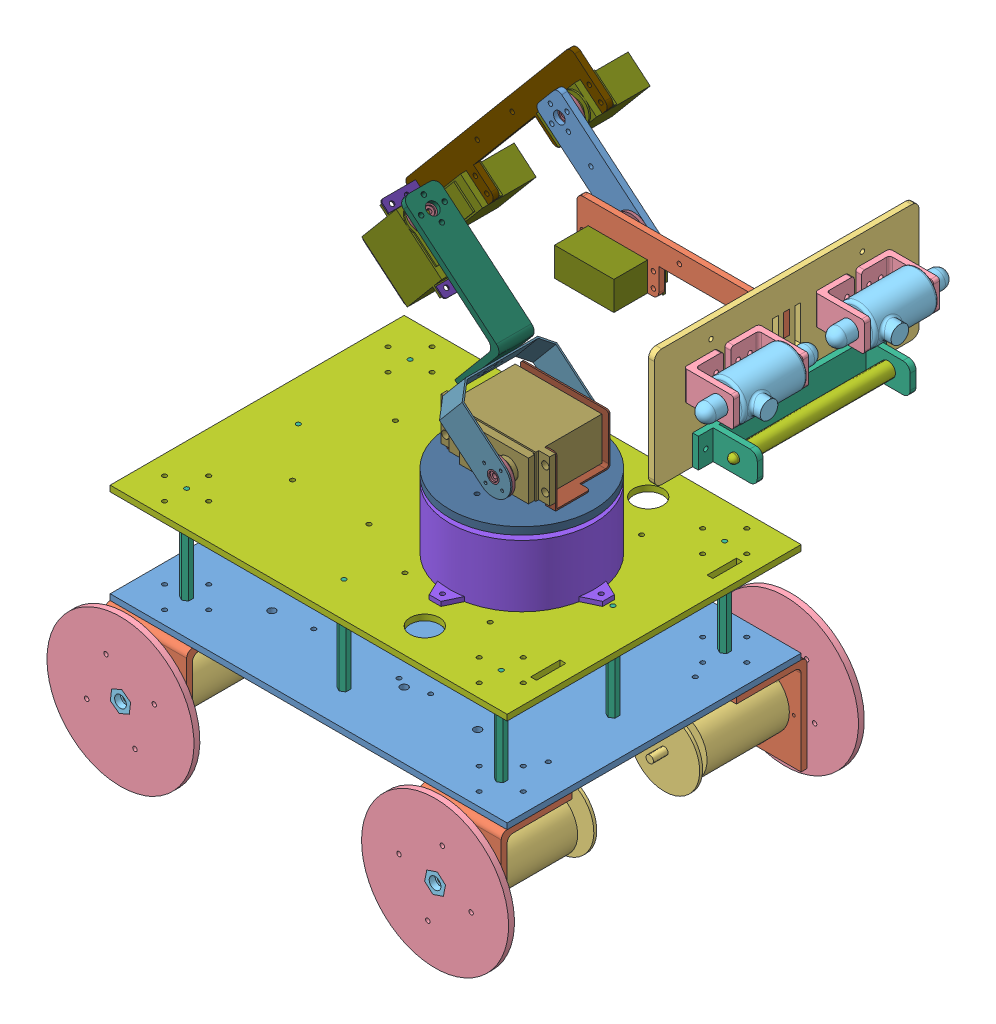
SolidWorks assembly robot_config5, configuration Default. Lengths in mm.
Overall size (452.85 463.23 242).
55 component instances, 25 part files, 137 mates.
Components (placement in the parent):
- base_odroid_down_fix-1: base_odroid_down_fix [Default] at (39.4639 122.941 229.7749) x (1 0 0) z (0 -1 0) size (270 200 4)
- link_motor_1_port-1: link_motor_1_port [Default] at (221.3654 112.3394 287.3354) x (0 0 -1) z (1 0 0) size (48 66 56)
- motor_dc_NISCA-1: motor_dc_NISCA [Default] at (244.2642 39.7289 313.6416) x (0 -1 0) z (0 0 -1) size (54 48 92)
- roda_shaft-1: roda_shaft [Default] at (185.8398 121.6563 330.6416) x (-0.980223 0.197896 0) z (0 0 1) size (100 100 4)
- shaft_adapter_5mm-1: shaft_adapter_5mm [Default] at (248.7954 72.9583 317.6416) x (0.980223 -0.197896 0) z (0 0 1) size (13 15.01 17)
- link_motor_1_port-2: link_motor_1_port [Default] at (221.3654 112.3394 139.9479) x (0 0 1) z (-1 0 0) size (48 66 56)
- motor_dc_NISCA-2: motor_dc_NISCA [Default] at (198.4666 39.7289 113.6416) x (0 -1 0) z (0 0 1) size (54 48 92)
- shaft_adapter_5mm-3: shaft_adapter_5mm [Default] at (238.0112 59.5291 109.6416) x (0.404857 -0.91438 0) z (0 0 -1) size (13 15.01 17)
- roda_shaft-2: roda_shaft [Default] at (222.1063 135.748 96.6416) x (0.589448 0.807807 0) z (0 0 -1) size (100 100 4)
- link_motor_1_port-5: link_motor_1_port [Default] at (7.3654 112.3394 287.3354) x (0 0 -1) z (1 0 0) size (48 66 56)
- motor_dc_NISCA-5: motor_dc_NISCA [Default] at (-15.5334 128.1531 313.6416) x (0 1 0) z (0 0 -1) size (54 48 92)
- roda_shaft-5: roda_shaft [Default] at (51.5287 56.8466 334.6416) x (0.393495 -0.919327 0) z (0 0 -1) size (100 100 4)
- shaft_adapter_5mm-6: shaft_adapter_5mm [Default] at (0.8367 112.7577 317.6416) x (-0.393495 0.919327 0) z (0 0 1) size (13 15.01 17)
- link_motor_1_port-6: link_motor_1_port [Default] at (7.3654 112.3394 139.9479) x (0 0 1) z (-1 0 0) size (48 66 56)
- motor_dc_NISCA-6: motor_dc_NISCA [Default] at (-15.5334 39.7289 113.6416) x (0 -1 0) z (0 0 1) size (54 48 92)
- roda_shaft-6: roda_shaft [Default] at (45.258 48.6046 96.6416) x (0.202799 -0.97922 0) z (0 0 -1) size (100 100 4)
- shaft_adapter_5mm-7: shaft_adapter_5mm [Default] at (36.6325 79.8838 109.6416) x (0.949429 -0.313981 0) z (0 0 -1) size (13 15.01 17)
- spacer_6cm-2: spacer_6cm [Default] at (221.7099 182.941 288.7798) x (0.5 0 -0.866025) z (0 -1 0) size (6 6.93 68)
- spacer_6cm-3: spacer_6cm [Default] at (114.7099 182.941 288.7798) x (0.5 0 -0.866025) z (0 -1 0) size (6 6.93 68)
- spacer_6cm-4: spacer_6cm [Default] at (7.7099 182.941 288.7798) x (0.5 0 -0.866025) z (0 -1 0) size (6 6.93 68)
- spacer_6cm-5: spacer_6cm [Default] at (221.7099 182.941 212.7798) x (0.5 0 -0.866025) z (0 -1 0) size (6 6.93 68)
- spacer_6cm-7: spacer_6cm [Default] at (7.7099 182.941 212.7798) x (0.5 0 -0.866025) z (0 -1 0) size (6 6.93 68)
- spacer_6cm-8: spacer_6cm [Default] at (221.7099 182.941 136.7798) x (0.5 0 -0.866025) z (0 -1 0) size (6 6.93 68)
- spacer_6cm-9: spacer_6cm [Default] at (114.7099 182.941 136.7798) x (0.5 0 -0.866025) z (0 -1 0) size (6 6.93 68)
- spacer_6cm-10: spacer_6cm [Default] at (7.7099 182.941 136.7798) x (0.5 0 -0.866025) z (0 -1 0) size (6 6.93 68)
- base_odroid_up_fix-1: base_odroid_up_fix [Default] at (186.1287 186.941 197.5083) x (-1 0 0) z (0 -1 0) size (270 200 4)
- base_arm-1: base_arm [Default] at (159.3654 194.0898 219.4289) x (0 0 1) z (-1 0 0) size (118.01 42 118.01)
- servo_hs422-1: servo_hs422 [Default] at (169.6524 210.6756 203.7356) x (0 0 1) z (-1 0 0) size (19.81 42.14 58.23)
- link1_arm-1: link1_arm [Default] at (132.7148 232.0663 213.6416) x (-1 0 0) z (0 1 0) size (98 98 12)
- bracket_servo_hs755-1: bracket_servo_hs755 [Default] at (196.3654 266.4802 252.854) x (0 0 1) z (-1 0 0) size (44 34 74)
- servo_hs755-1: servo_hs755 [Default] at (169.4663 211.9363 188.6416) x (0 -1 0) z (0 0 1) size (29 74 56.99)
- servo_horn_general-1: servo_horn_general [Default] at (212.6751 229.4848 247.6316) x (0.766044 -0.642788 0) z (0 0 -1) size (24 24 6)
- link2_ubracket-2: link2_ubracket [Default] at (137.2903 272.9307 202.3382) x (0 0 -1) z (0.642788 0.766044 0) size (66 59 24)
- link2_fix-2: link2_fix [Default] at (95.2497 313.4968 203.2174) x (-0.642788 -0.766044 0) z (0 0 1) size (45.14 89 24)
- servo_horn_general-2: servo_horn_general [Default] at (133.6428 328.2076 212.0424) x (0.766044 -0.642788 0) z (-0.642788 -0.766044 0) size (24 24 6)
- servo_hs645-2: servo_hs645 [Default] at (36.495 351.8235 228.4385) x (-0.766044 0.642788 0) z (0.642788 0.766044 0) size (53.34 19.56 42.35)
- bracket_servo_645-2: bracket_servo_645 [Default] at (85.4438 371.1492 209.3754) x (0.642788 0.766044 0) z (0.766044 -0.642788 0) size (34 24 57)
- servo_horn_general-3: servo_horn_general [Default] at (114.2751 302.95 201.2504) x (0.573576 -0.819152 0) z (0 0 -1) size (24 24 6)
- servo_hs645-3: servo_hs645 [Default] at (67.4404 298.0108 156.8959) x (-0.642788 -0.766044 0) z (0 0 1) size (53.34 19.56 42.35)
- link4_fix-1: link4_fix [Default] at (217.9489 486.4381 185.4709) x (0.642788 0.766044 0) z (0 0 1) size (176.25 35 4)
- servo_hs645-4: servo_hs645 [Default] at (193.9848 489.1669 156.8959) x (0.642788 0.766044 0) z (0 0 1) size (53.34 19.56 42.35)
- link5_fix-1: link5_fix [Default] at (223.23 467.7473 201.2504) x (0.642788 0.766044 0) z (0 0 1) size (24 90 4)
- servo_horn_general-4: servo_horn_general [Default] at (138.7232 475.3817 201.2504) x (-0.766044 0.642788 0) z (0 0 -1) size (24 24 6)
- servo_horn_general-5: servo_horn_general [Default] at (260.8198 372.9304 205.2504) x (0.766044 -0.642788 0) z (0 0 1) size (24 24 6)
- servo_hs645-5: servo_hs645 [Default] at (184.1852 418.5973 249.6049) x (-1 0 0) z (0 0 -1) size (53.34 19.56 42.35)
- link6_eff-1: link6_eff [Default] at (190.8717 398.4857 226.6809) x (-1 0 0) z (0 0 -1) size (140.63 35 4)
- base_link_effector_fix-2: base_link_effector_fix [Default] at (346.5728 431.9683 227.3815) x (0 0 -1) z (1 0 0) size (180 80 4)
- base_webcam_fix1-2: base_webcam_fix1 [Default] at (350.5728 432.3512 294.6809) x (0 0 -1) z (0 -1 0) size (23 34 20)
- base_webcam_fix1-3: base_webcam_fix1 [Default] at (350.5728 412.3512 243.6809) x (0 0 1) z (0 1 0) size (23 34 20)
- base_webcam_fix1-4: base_webcam_fix1 [Default] at (350.5728 432.3512 205.6809) x (0 0 -1) z (0 -1 0) size (23 34 20)
- base_webcam_fix1-5: base_webcam_fix1 [Default] at (350.5728 412.3512 154.6809) x (0 0 1) z (0 1 0) size (23 34 20)
- webcam_sturdy-3: webcam_sturdy [Default] at (374.5728 422.3512 243.37) x (0 0 -1) z (1 0 0) size (79 27 33.5)
- webcam_sturdy-4: webcam_sturdy [Default] at (374.5728 422.3512 154.37) x (0 0 -1) z (1 0 0) size (79 27 33.5)
- base_GM-1: base_GM [Default] at (358.8201 390.8512 184.9491) x (0 0 -1) z (0 -1 0) size (128 34 20)
- tabung_GM-1: tabung_GM [Default] at (418.1614 373.2473 174.6809) x (0.998525 0.054289 0) z (0 0 1) size (10 10 116)
Mates (geometry in assembly coordinates):
- Coincident1: coincident anti-aligned: plane of link_motor_1_port-1 through (193.3654 52.941 313.6416) normal (0 0 -1); plane of motor_dc_NISCA-1 through (221.3654 83.941 313.6416) normal (0 0 1)
- Concentric1: concentric aligned: cylinder of link_motor_1_port-1 through (221.3654 83.941 317.6416) axis (0 0 -1) radius 9.5; cylinder of motor_dc_NISCA-1 through (221.3654 83.941 317.6416) axis (0 0 -1) radius 9
- Concentric2: concentric anti-aligned: cylinder of link_motor_1_port-1 through (221.3654 106.941 317.6416) axis (0 0 -1) radius 1; cylinder of motor_dc_NISCA-1 through (221.3654 106.941 311.6416) axis (0 0 1) radius 1.5
- Coincident2: coincident anti-aligned: plane of motor_dc_NISCA-1 through (244.2642 39.7289 317.6416) normal (0 0 1); plane of shaft_adapter_5mm-1 through (221.3654 83.941 317.6416) normal (0 0 -1)
- Concentric4: concentric aligned: cylinder of motor_dc_NISCA-1 through (221.3654 83.941 330.6416) axis (0 0 -1) radius 2.5; cylinder of shaft_adapter_5mm-1 through (221.3654 83.941 330.6416) axis (0 0 -1) radius 2.5
- Coincident3: coincident anti-aligned: plane of roda_shaft-1 through (222.8507 91.2981 330.6416) normal (0.318728 -0.947846 0); plane of shaft_adapter_5mm-1 through (222.8507 91.2981 334.6416) normal (-0.318728 0.947846 0)
- Coincident4: coincident aligned: plane of roda_shaft-1 through (221.3654 83.941 334.6416) normal (0 0 1); plane of shaft_adapter_5mm-1 through (248.7954 72.9583 334.6416) normal (0 0 1)
- Coincident7: coincident anti-aligned: plane of roda_shaft-1 through (214.2513 81.5488 330.6416) normal (0.661495 0.74995 0); plane of shaft_adapter_5mm-1 through (214.2513 81.5488 334.6416) normal (-0.661495 -0.74995 0)
- Coincident8: coincident anti-aligned: plane of link_motor_1_port-2 through (249.3654 52.941 113.6416) normal (0 0 1); plane of motor_dc_NISCA-2 through (221.3654 83.941 113.6416) normal (0 0 -1)
- Concentric5: concentric aligned: cylinder of link_motor_1_port-2 through (221.3654 83.941 109.6416) axis (0 0 1) radius 9.5; cylinder of motor_dc_NISCA-2 through (221.3654 83.941 109.6416) axis (0 0 1) radius 9
- Concentric7: concentric anti-aligned: cylinder of link_motor_1_port-2 through (221.3654 106.941 109.6416) axis (0 0 1) radius 1; cylinder of motor_dc_NISCA-2 through (221.3654 106.941 115.6416) axis (0 0 -1) radius 1.5
- Coincident9: coincident anti-aligned: plane of base_odroid_down_fix-1 through (39.4639 118.941 229.7749) normal (0 -1 0); plane of link_motor_1_port-1 through (193.3654 118.941 269.6416) normal (0 1 0)
- Concentric8: concentric anti-aligned: cylinder of base_odroid_down_fix-1 through (206.3654 118.941 289.6416) axis (0 1 0) radius 1.5; cylinder of link_motor_1_port-1 through (206.3654 118.941 289.6416) axis (0 -1 0) radius 1.5
- Concentric9: concentric anti-aligned: cylinder of base_odroid_down_fix-1 through (236.3654 118.941 289.6416) axis (0 1 0) radius 1.5; cylinder of link_motor_1_port-1 through (236.3654 118.941 289.6416) axis (0 -1 0) radius 1.5
- Coincident11: coincident aligned: plane of shaft_adapter_5mm-3 through (238.0112 59.5291 92.6416) normal (0 0 -1); plane of roda_shaft-2 through (221.3654 83.941 92.6416) normal (0 0 -1)
- Coincident12: coincident anti-aligned: plane of shaft_adapter_5mm-3 through (220.5655 76.4782 92.6416) normal (-0.589448 -0.807807 0); plane of roda_shaft-2 through (220.5655 76.4782 96.6416) normal (0.589448 0.807807 0)
- Coincident13: coincident anti-aligned: plane of shaft_adapter_5mm-3 through (228.2283 86.9797 92.6416) normal (0.994305 -0.106573 0); plane of roda_shaft-2 through (228.2283 86.9797 96.6416) normal (-0.994305 0.106573 0)
- Coincident14: coincident anti-aligned: plane of motor_dc_NISCA-2 through (198.4666 39.7289 109.6416) normal (0 0 -1); plane of shaft_adapter_5mm-3 through (221.3654 83.941 109.6416) normal (0 0 1)
- Concentric10: concentric aligned: cylinder of motor_dc_NISCA-2 through (221.3654 83.941 96.6416) axis (0 0 1) radius 2.5; cylinder of shaft_adapter_5mm-3 through (221.3654 83.941 96.6416) axis (0 0 1) radius 2.5
- Coincident15: coincident anti-aligned: plane of base_odroid_down_fix-1 through (39.4639 118.941 229.7749) normal (0 -1 0); plane of link_motor_1_port-2 through (249.3654 118.941 157.6416) normal (0 1 0)
- Concentric11: concentric anti-aligned: cylinder of base_odroid_down_fix-1 through (206.3654 118.941 137.6416) axis (0 1 0) radius 1.5; cylinder of link_motor_1_port-2 through (206.3654 118.941 137.6416) axis (0 -1 0) radius 1.5
- Concentric12: concentric anti-aligned: cylinder of base_odroid_down_fix-1 through (236.3654 118.941 137.6416) axis (0 1 0) radius 1.5; cylinder of link_motor_1_port-2 through (236.3654 118.941 137.6416) axis (0 -1 0) radius 1.5
- Coincident16: coincident anti-aligned: plane of link_motor_1_port-5 through (-20.6346 52.941 313.6416) normal (0 0 -1); plane of motor_dc_NISCA-5 through (7.3654 83.941 313.6416) normal (0 0 1)
- Concentric13: concentric aligned: cylinder of link_motor_1_port-5 through (7.3654 83.941 317.6416) axis (0 0 -1) radius 9.5; cylinder of motor_dc_NISCA-5 through (7.3654 83.941 317.6416) axis (0 0 -1) radius 9
- Concentric14: concentric anti-aligned: cylinder of link_motor_1_port-5 through (7.3654 106.941 317.6416) axis (0 0 -1) radius 1; cylinder of motor_dc_NISCA-5 through (7.3654 106.941 311.6416) axis (0 0 1) radius 1.5
- Concentric16: concentric aligned: cylinder of motor_dc_NISCA-5 through (7.3654 83.941 330.6416) axis (0 0 -1) radius 2.5; cylinder of shaft_adapter_5mm-6 through (7.3654 83.941 330.6416) axis (0 0 -1) radius 2.5
- Coincident17: coincident anti-aligned: plane of motor_dc_NISCA-5 through (-15.5334 128.1531 317.6416) normal (0 0 1); plane of shaft_adapter_5mm-6 through (7.3654 83.941 317.6416) normal (0 0 -1)
- Coincident18: coincident anti-aligned: plane of roda_shaft-5 through (6.4731 76.4887 334.6416) normal (0.599413 0.80044 0); plane of shaft_adapter_5mm-6 through (0.4653 80.9876 334.6416) normal (-0.599413 -0.80044 0)
- Coincident19: coincident aligned: plane of roda_shaft-5 through (7.3654 83.941 334.6416) normal (0 0 1); plane of shaft_adapter_5mm-6 through (0.8367 112.7577 334.6416) normal (0 0 1)
- Coincident20: coincident anti-aligned: plane of roda_shaft-5 through (1.3576 88.44 334.6416) normal (0.393495 -0.919327 0); plane of shaft_adapter_5mm-6 through (8.2577 91.3934 334.6416) normal (-0.393495 0.919327 0)
- Coincident21: coincident anti-aligned: plane of base_odroid_down_fix-1 through (39.4639 118.941 229.7749) normal (0 -1 0); plane of link_motor_1_port-5 through (-20.6346 118.941 269.6416) normal (0 1 0)
- Concentric17: concentric anti-aligned: cylinder of base_odroid_down_fix-1 through (-7.6346 118.941 289.6416) axis (0 1 0) radius 1.5; cylinder of link_motor_1_port-5 through (-7.6346 118.941 289.6416) axis (0 -1 0) radius 1.5
- Concentric18: concentric anti-aligned: cylinder of base_odroid_down_fix-1 through (22.3654 118.941 289.6416) axis (0 1 0) radius 1.5; cylinder of link_motor_1_port-5 through (22.3654 118.941 289.6416) axis (0 -1 0) radius 1.5
- Coincident22: coincident anti-aligned: plane of link_motor_1_port-6 through (35.3654 52.941 113.6416) normal (0 0 1); plane of motor_dc_NISCA-6 through (7.3654 83.941 113.6416) normal (0 0 -1)
- Concentric19: concentric aligned: cylinder of link_motor_1_port-6 through (7.3654 83.941 109.6416) axis (0 0 1) radius 9.5; cylinder of motor_dc_NISCA-6 through (7.3654 83.941 109.6416) axis (0 0 1) radius 9
- Concentric20: concentric anti-aligned: cylinder of link_motor_1_port-6 through (7.3654 106.941 109.6416) axis (0 0 1) radius 1; cylinder of motor_dc_NISCA-6 through (7.3654 106.941 115.6416) axis (0 0 -1) radius 1.5
- Concentric21: concentric aligned: cylinder of motor_dc_NISCA-6 through (7.3654 83.941 96.6416) axis (0 0 1) radius 2.5; cylinder of shaft_adapter_5mm-7 through (7.3654 83.941 96.6416) axis (0 0 1) radius 2.5
- Coincident23: coincident anti-aligned: plane of motor_dc_NISCA-6 through (-15.5334 39.7289 109.6416) normal (0 0 -1); plane of shaft_adapter_5mm-7 through (7.3654 83.941 109.6416) normal (0 0 1)
- Coincident24: coincident aligned: plane of roda_shaft-6 through (7.3654 83.941 92.6416) normal (0 0 -1); plane of shaft_adapter_5mm-7 through (36.6325 79.8838 92.6416) normal (0 0 -1)
- Coincident25: coincident anti-aligned: plane of roda_shaft-6 through (2.3724 89.5449 96.6416) normal (0.202799 -0.97922 0); plane of shaft_adapter_5mm-7 through (2.3724 89.5449 92.6416) normal (-0.202799 0.97922 0)
- Coincident26: coincident anti-aligned: plane of roda_shaft-6 through (5.0088 76.815 96.6416) normal (0.74663 0.665239 0); plane of shaft_adapter_5mm-7 through (5.0088 76.815 92.6416) normal (-0.74663 -0.665239 0)
- Coincident27: coincident anti-aligned: plane of base_odroid_down_fix-1 through (39.4639 118.941 229.7749) normal (0 -1 0); plane of link_motor_1_port-6 through (35.3654 118.941 157.6416) normal (0 1 0)
- Concentric22: concentric anti-aligned: cylinder of base_odroid_down_fix-1 through (-7.6346 118.941 137.6416) axis (0 1 0) radius 1.5; cylinder of link_motor_1_port-6 through (-7.6346 118.941 137.6416) axis (0 -1 0) radius 1.5
- Concentric23: concentric anti-aligned: cylinder of base_odroid_down_fix-1 through (22.3654 118.941 137.6416) axis (0 1 0) radius 1.5; cylinder of link_motor_1_port-6 through (22.3654 118.941 137.6416) axis (0 -1 0) radius 1.5
- Concentric24: concentric aligned: cylinder of base_odroid_down_fix-1 through (221.3654 118.941 289.6416) axis (0 1 0) radius 1.5; cylinder of spacer_6cm-2 through (221.3654 118.941 289.6416) axis (0 1 0) radius 1.5
- Coincident28: coincident anti-aligned: plane of base_odroid_down_fix-1 through (39.4639 122.941 229.7749) normal (0 1 0); plane of spacer_6cm-2 through (221.7099 122.941 288.7798) normal (0 -1 0)
- Parallel2: parallel aligned: plane of base_odroid_down_fix-1 through (249.3654 118.941 229.7749) normal (1 0 0); plane of spacer_6cm-2 through (224.3654 122.941 287.9096) normal (1 0 0)
- Concentric25: concentric anti-aligned: cylinder of spacer_6cm-2 through (221.3654 186.941 289.6416) axis (0 -1 0) radius 1.5; cylinder of base_odroid_up_fix-1 through (221.3654 182.941 289.6416) axis (0 1 0) radius 1.5
- Concentric26: concentric anti-aligned: cylinder of spacer_6cm-7 through (7.3654 186.941 213.6416) axis (0 -1 0) radius 1.5; cylinder of base_odroid_up_fix-1 through (7.3654 182.941 213.6416) axis (0 1 0) radius 1.5
- Coincident29: coincident anti-aligned: plane of spacer_6cm-2 through (221.7099 182.941 288.7798) normal (0 1 0); plane of base_odroid_up_fix-1 through (186.1287 182.941 197.5083) normal (0 -1 0)
- Coincident31: coincident anti-aligned: plane of base_arm-1 through (159.3654 225.941 213.6416) normal (0 -1 0); plane of servo_hs422-1 through (169.6524 225.941 203.7356) normal (0 1 0)
- Parallel3: parallel aligned: plane of base_odroid_up_fix-1 through (249.3654 182.941 197.5083) normal (1 0 0); plane of servo_hs422-1 through (189.5914 210.6756 223.5476) normal (1 0 0)
- Coincident33: coincident anti-aligned: plane of base_odroid_up_fix-1 through (186.1287 186.941 197.5083) normal (0 1 0); plane of base_arm-1 through (159.3654 186.941 259.6416) normal (0 -1 0)
- Concentric28: concentric anti-aligned: cylinder of base_odroid_up_fix-1 through (213.3654 182.941 213.6416) axis (0 1 0) radius 1.5; cylinder of base_arm-1 through (213.3654 189.941 213.6416) axis (0 -1 0) radius 1.5
- Concentric29: concentric anti-aligned: cylinder of base_odroid_up_fix-1 through (159.3654 182.941 159.6416) axis (0 1 0) radius 1.5; cylinder of base_arm-1 through (159.3654 189.941 159.6416) axis (0 -1 0) radius 1.5
- Parallel5: parallel aligned: plane of base_odroid_up_fix-1 through (186.1287 182.941 113.6416) normal (0 0 -1); plane of servo_hs422-1 through (169.6524 210.6756 203.7356) normal (0 0 -1)
- Concentric30: concentric aligned: cylinder of base_arm-1 through (159.3654 225.941 213.6416) axis (0 1 0) radius 5.4623; cylinder of servo_hs422-1 through (159.3654 202.0734 213.6416) axis (0 1 0) radius 6.4897
- Concentric31: concentric aligned: cylinder of servo_hs422-1 through (159.3654 212.8107 213.6416) axis (0 1 0) radius 2.8131; cylinder of link1_arm-1 through (159.3654 228.0663 213.6416) axis (0 1 0) radius 3
- Coincident36: coincident anti-aligned: plane of servo_hs422-1 through (169.6524 232.0663 223.5476) normal (0 1 0); plane of link1_arm-1 through (159.3654 232.0663 213.6416) normal (0 -1 0)
- Concentric32: concentric aligned: cylinder of link1_arm-1 through (159.3654 240.0663 213.6416) axis (0 -1 0) radius 4; cylinder of bracket_servo_hs755-1 through (159.3654 238.0663 213.6416) axis (0 -1 0) radius 4
- Coincident38: coincident anti-aligned: plane of link1_arm-1 through (159.3654 237.0663 213.6416) normal (0 1 0); plane of bracket_servo_hs755-1 through (122.3654 237.0663 183.6416) normal (0 -1 0)
- Concentric33: concentric anti-aligned: cylinder of link1_arm-1 through (151.3654 232.0663 213.6416) axis (0 1 0) radius 1.5; cylinder of bracket_servo_hs755-1 through (151.3654 238.0663 213.6416) axis (0 -1 0) radius 1.5
- Coincident40: coincident anti-aligned: plane of bracket_servo_hs755-1 through (122.3654 237.0663 227.6416) normal (0 0 1); plane of servo_hs755-1 through (169.4663 211.9363 227.6416) normal (0 0 -1)
- Concentric36: concentric aligned: cylinder of bracket_servo_hs755-1 through (125.3654 248.5663 226.6416) axis (0 0 1) radius 1.5; cylinder of servo_hs755-1 through (125.3654 248.5663 227.6416) axis (0 0 1) radius 2.5
- Concentric37: concentric aligned: cylinder of bracket_servo_hs755-1 through (193.3654 264.5663 226.6416) axis (0 0 1) radius 1.5; cylinder of servo_hs755-1 through (193.3654 264.5663 227.6416) axis (0 0 1) radius 2.5
- Concentric39: concentric anti-aligned: cylinder of servo_hs755-1 through (174.8654 257.0663 245.6316) axis (0 0 -1) radius 3; cylinder of servo_horn_general-1 through (174.8654 257.0663 242.6316) axis (0 0 1) radius 3
- Coincident41: coincident anti-aligned: plane of servo_hs755-1 through (174.8654 257.0663 245.6316) normal (0 0 1); plane of servo_horn_general-1 through (174.8654 257.0663 245.6316) normal (0 0 -1)
- Concentric40: concentric anti-aligned: cylinder of servo_horn_general-1 through (174.8654 257.0663 248.6316) axis (0 0 -1) radius 4; cylinder of link2_ubracket-2 through (174.8654 257.0663 247.6316) axis (0 0 1) radius 4
- Coincident42: coincident anti-aligned: plane of servo_horn_general-1 through (174.8654 257.0663 247.6316) normal (0 0 1); plane of link2_ubracket-2 through (154.1038 290.1523 247.6316) normal (0 0 -1)
- Concentric41: concentric aligned: cylinder of servo_horn_general-1 through (169.7231 250.9379 245.6316) axis (0 0 1) radius 0.5; cylinder of link2_ubracket-2 through (169.7231 250.9379 247.6316) axis (0 0 1) radius 1
- Coincident46: coincident anti-aligned: plane of link2_ubracket-2 through (146.5747 296.4698 239.2174) normal (-0.766044 0.642788 0); plane of link2_fix-2 through (133.7526 281.189 227.2174) normal (0.766044 -0.642788 0)
- Concentric45: concentric anti-aligned: cylinder of link2_ubracket-2 through (139.6273 286.6345 215.2174) axis (-0.766044 0.642788 0) radius 4; cylinder of link2_fix-2 through (135.7971 289.8485 215.2174) axis (0.766044 -0.642788 0) radius 4
- Concentric46: concentric anti-aligned: cylinder of link2_ubracket-2 through (139.6273 286.6345 207.2174) axis (-0.766044 0.642788 0) radius 1; cylinder of link2_fix-2 through (135.7971 289.8485 207.2174) axis (0.766044 -0.642788 0) radius 1.5
- Coincident47: coincident anti-aligned: plane of servo_horn_general-2 through (96.5884 356.6891 215.2174) normal (-0.642788 -0.766044 0); plane of servo_hs645-2 through (96.5884 356.6891 215.2174) normal (0.642788 0.766044 0)
- Concentric48: concentric anti-aligned: cylinder of servo_horn_general-2 through (94.66 354.391 215.2174) axis (0.642788 0.766044 0) radius 3; cylinder of servo_hs645-2 through (96.5884 356.6891 215.2174) axis (-0.642788 -0.766044 0) radius 2.9972
- Coincident48: coincident anti-aligned: plane of link2_fix-2 through (118.3565 341.0343 227.2174) normal (-0.642788 -0.766044 0); plane of servo_horn_general-2 through (97.8739 358.2212 215.2174) normal (0.642788 0.766044 0)
- Concentric49: concentric anti-aligned: cylinder of link2_fix-2 through (97.8739 358.2212 215.2174) axis (0.642788 0.766044 0) radius 4; cylinder of servo_horn_general-2 through (98.5167 358.9872 215.2174) axis (-0.642788 -0.766044 0) radius 4
- Concentric50: concentric aligned: cylinder of link2_fix-2 through (97.8739 358.2212 207.2174) axis (0.642788 0.766044 0) radius 1.5; cylinder of servo_horn_general-2 through (96.5884 356.6891 207.2174) axis (0.642788 0.766044 0) radius 0.5
- Coincident50: coincident anti-aligned: plane of servo_hs645-2 through (54.8627 373.7132 228.4385) normal (0.642788 0.766044 0); plane of bracket_servo_645-2 through (117.7355 320.9567 202.2504) normal (-0.642788 -0.766044 0)
- Concentric51: concentric aligned: cylinder of servo_hs645-2 through (75.3777 352.3544 220.5514) axis (0.642788 0.766044 0) radius 2.5019; cylinder of bracket_servo_645-2 through (76.4287 353.6069 220.5514) axis (0.642788 0.766044 0) radius 1.5
- Concentric52: concentric aligned: cylinder of servo_hs645-2 through (112.347 321.3335 220.5514) axis (0.642788 0.766044 0) radius 2.5019; cylinder of bracket_servo_645-2 through (113.398 322.586 220.5514) axis (0.642788 0.766044 0) radius 1.5
- Concentric53: concentric aligned: cylinder of bracket_servo_645-2 through (84.8923 339.3775 202.2504) axis (0 0 -1) radius 4; cylinder of servo_horn_general-3 through (84.8923 339.3775 202.2504) axis (0 0 -1) radius 4
- Coincident51: coincident anti-aligned: plane of bracket_servo_645-2 through (99.0946 298.7414 201.2504) normal (0 0 -1); plane of servo_horn_general-3 through (84.8923 339.3775 201.2504) normal (0 0 1)
- Concentric54: concentric anti-aligned: cylinder of bracket_servo_645-2 through (79.75 333.2492 202.2504) axis (0 0 -1) radius 1.5; cylinder of servo_horn_general-3 through (79.75 333.2492 199.2504) axis (0 0 1) radius 0.5
- Coincident52: coincident anti-aligned: plane of servo_horn_general-3 through (84.8923 339.3775 199.2504) normal (0 0 -1); plane of servo_hs645-3 through (84.8923 339.3775 199.2504) normal (0 0 1)
- Concentric55: concentric anti-aligned: cylinder of servo_horn_general-3 through (84.8923 339.3775 196.2504) axis (0 0 1) radius 3; cylinder of servo_hs645-3 through (84.8923 339.3775 199.2504) axis (0 0 -1) radius 2.9972
- Concentric61: concentric anti-aligned: cylinder of servo_hs645-4 through (176.5329 447.8002 199.2504) axis (0 0 -1) radius 2.9972; cylinder of servo_horn_general-4 through (176.5329 447.8002 196.2504) axis (0 0 1) radius 3
- Coincident56: coincident anti-aligned: plane of servo_hs645-4 through (176.5329 447.8002 199.2504) normal (0 0 1); plane of servo_horn_general-4 through (176.5329 447.8002 199.2504) normal (0 0 -1)
- Coincident57: coincident anti-aligned: plane of link5_fix-1 through (223.23 467.7473 201.2504) normal (0 0 -1); plane of servo_horn_general-4 through (176.5329 447.8002 201.2504) normal (0 0 1)
- Concentric62: concentric anti-aligned: cylinder of link5_fix-1 through (176.5329 447.8002 201.2504) axis (0 0 1) radius 4; cylinder of servo_horn_general-4 through (176.5329 447.8002 202.2504) axis (0 0 -1) radius 4
- Concentric63: concentric aligned: cylinder of link5_fix-1 through (181.6752 453.9286 201.2504) axis (0 0 1) radius 1.5; cylinder of servo_horn_general-4 through (181.6752 453.9286 199.2504) axis (0 0 1) radius 0.5
- Concentric64: concentric anti-aligned: cylinder of servo_horn_general-5 through (227.0918 405.3762 210.2504) axis (0 0 -1) radius 3; cylinder of servo_hs645-5 through (227.0918 405.3762 207.2504) axis (0 0 1) radius 2.9972
- Coincident58: coincident anti-aligned: plane of servo_horn_general-5 through (227.0918 405.3762 207.2504) normal (0 0 1); plane of servo_hs645-5 through (227.0918 405.3762 207.2504) normal (0 0 -1)
- Coincident59: coincident anti-aligned: plane of link5_fix-1 through (223.23 467.7473 205.2504) normal (0 0 1); plane of servo_horn_general-5 through (227.0918 405.3762 205.2504) normal (0 0 -1)
- Concentric65: concentric aligned: cylinder of link5_fix-1 through (227.0918 405.3762 201.2504) axis (0 0 1) radius 4; cylinder of servo_horn_general-5 through (227.0918 405.3762 204.2504) axis (0 0 1) radius 4
- Concentric66: concentric anti-aligned: cylinder of link5_fix-1 through (221.9495 399.2479 201.2504) axis (0 0 1) radius 1.5; cylinder of servo_horn_general-5 through (221.9495 399.2479 207.2504) axis (0 0 -1) radius 0.5
- Coincident60: coincident anti-aligned: plane of servo_hs645-5 through (184.1852 418.5973 222.6809) normal (0 0 1); plane of link6_eff-1 through (190.8717 398.4857 222.6809) normal (0 0 -1)
- Concentric67: concentric aligned: cylinder of servo_hs645-5 through (213.6298 400.5502 224.2049) axis (0 0 -1) radius 2.5019; cylinder of link6_eff-1 through (213.6298 400.5502 226.6809) axis (0 0 -1) radius 1.5
- Concentric68: concentric aligned: cylinder of servo_hs645-5 through (261.8898 400.5502 224.2049) axis (0 0 -1) radius 2.5019; cylinder of link6_eff-1 through (261.8898 400.5502 226.6809) axis (0 0 -1) radius 1.5
- Coincident61: coincident aligned: plane of link6_eff-1 through (350.5728 398.4857 222.6809) normal (1 0 0); plane of base_link_effector_fix-2 through (350.5728 431.9683 227.3815) normal (1 0 0)
- Coincident62: coincident anti-aligned: plane of link6_eff-1 through (190.8717 398.4857 222.6809) normal (0 0 -1); plane of base_link_effector_fix-2 through (346.5728 430.8512 222.6809) normal (0 0 1)
- Coincident63: coincident anti-aligned: plane of link6_eff-1 through (190.8717 430.8512 222.6809) normal (0 1 0); plane of base_link_effector_fix-2 through (346.5728 430.8512 226.6809) normal (0 -1 0)
- Coincident72: coincident anti-aligned: plane of base_link_effector_fix-2 through (350.5728 431.9683 227.3815) normal (1 0 0); plane of base_webcam_fix1-2 through (350.5728 412.3512 294.6809) normal (-1 0 0)
- Concentric71: concentric anti-aligned: cylinder of base_link_effector_fix-2 through (350.5728 422.3512 276.6809) axis (-1 0 0) radius 1.5; cylinder of base_webcam_fix1-2 through (350.5728 422.3512 276.6809) axis (1 0 0) radius 1.5
- Concentric72: concentric anti-aligned: cylinder of base_link_effector_fix-2 through (350.5728 422.3512 284.6809) axis (-1 0 0) radius 1.5; cylinder of base_webcam_fix1-2 through (350.5728 422.3512 284.6809) axis (1 0 0) radius 1.5
- Coincident73: coincident anti-aligned: plane of base_link_effector_fix-2 through (350.5728 431.9683 227.3815) normal (1 0 0); plane of base_webcam_fix1-3 through (350.5728 432.3512 243.6809) normal (-1 0 0)
- Concentric73: concentric anti-aligned: cylinder of base_link_effector_fix-2 through (350.5728 422.3512 253.6809) axis (-1 0 0) radius 1.5; cylinder of base_webcam_fix1-3 through (350.5728 422.3512 253.6809) axis (1 0 0) radius 1.5
- Concentric74: concentric anti-aligned: cylinder of base_link_effector_fix-2 through (350.5728 422.3512 261.6809) axis (-1 0 0) radius 1.5; cylinder of base_webcam_fix1-3 through (350.5728 422.3512 261.6809) axis (1 0 0) radius 1.5
- Coincident74: coincident anti-aligned: plane of base_link_effector_fix-2 through (350.5728 431.9683 227.3815) normal (1 0 0); plane of base_webcam_fix1-4 through (350.5728 412.3512 205.6809) normal (-1 0 0)
- Concentric75: concentric anti-aligned: cylinder of base_link_effector_fix-2 through (350.5728 422.3512 187.6809) axis (-1 0 0) radius 1.5; cylinder of base_webcam_fix1-4 through (350.5728 422.3512 187.6809) axis (1 0 0) radius 1.5
- Concentric76: concentric anti-aligned: cylinder of base_link_effector_fix-2 through (350.5728 422.3512 195.6809) axis (-1 0 0) radius 1.5; cylinder of base_webcam_fix1-4 through (350.5728 422.3512 195.6809) axis (1 0 0) radius 1.5
- Coincident75: coincident anti-aligned: plane of base_link_effector_fix-2 through (350.5728 431.9683 227.3815) normal (1 0 0); plane of base_webcam_fix1-5 through (350.5728 432.3512 154.6809) normal (-1 0 0)
- Concentric77: concentric anti-aligned: cylinder of base_link_effector_fix-2 through (350.5728 422.3512 172.6809) axis (-1 0 0) radius 1.5; cylinder of base_webcam_fix1-5 through (350.5728 422.3512 172.6809) axis (1 0 0) radius 1.5
- Concentric78: concentric anti-aligned: cylinder of base_link_effector_fix-2 through (350.5728 422.3512 164.6809) axis (-1 0 0) radius 1.5; cylinder of base_webcam_fix1-5 through (350.5728 422.3512 164.6809) axis (1 0 0) radius 1.5
- Concentric79: concentric anti-aligned: cylinder of base_webcam_fix1-2 through (374.5728 422.3512 290.6809) axis (0 0 1) radius 6; cylinder of webcam_sturdy-3 through (374.5728 422.3512 308.6809) axis (0 0 -1) radius 6
- Coincident78: coincident anti-aligned: plane of base_webcam_fix1-3 through (354.5728 432.3512 247.6809) normal (0 0 1); plane of webcam_sturdy-3 through (374.5728 422.3512 247.6809) normal (0 0 -1)
- Parallel8: parallel aligned: plane of base_link_effector_fix-2 through (350.5728 431.9683 227.3815) normal (1 0 0); plane of webcam_sturdy-3 through (394.5728 422.3512 280.6809) normal (1 0 0)
- Concentric80: concentric anti-aligned: cylinder of base_webcam_fix1-4 through (374.5728 422.3512 201.6809) axis (0 0 1) radius 6; cylinder of webcam_sturdy-4 through (374.5728 422.3512 219.6809) axis (0 0 -1) radius 6
- Coincident80: coincident anti-aligned: plane of base_webcam_fix1-5 through (354.5728 432.3512 158.6809) normal (0 0 1); plane of webcam_sturdy-4 through (374.5728 422.3512 158.6809) normal (0 0 -1)
- Parallel9: parallel aligned: plane of base_link_effector_fix-2 through (350.5728 431.9683 227.3815) normal (1 0 0); plane of webcam_sturdy-4 through (394.5728 422.3512 191.6809) normal (1 0 0)
- Coincident82: coincident anti-aligned: plane of base_link_effector_fix-2 through (350.5728 431.9683 227.3815) normal (1 0 0); plane of base_GM-1 through (350.5728 370.8512 278.6809) normal (-1 0 0)
- Concentric81: concentric anti-aligned: cylinder of base_link_effector_fix-2 through (350.5728 380.8512 165.6809) axis (-1 0 0) radius 1.5; cylinder of base_GM-1 through (350.5728 380.8512 165.6809) axis (1 0 0) radius 1.5
- Concentric82: concentric anti-aligned: cylinder of base_link_effector_fix-2 through (350.5728 380.8512 283.6809) axis (-1 0 0) radius 1.5; cylinder of base_GM-1 through (350.5728 380.8512 283.6809) axis (1 0 0) radius 1.5
- Concentric83: concentric anti-aligned: cylinder of base_GM-1 through (369.5728 380.8512 174.6809) axis (0 0 -1) radius 3; cylinder of tabung_GM-1 through (369.5728 380.8512 166.6809) axis (0 0 1) radius 3
- Coincident83: coincident anti-aligned: plane of base_GM-1 through (384.5728 370.8512 274.6809) normal (0 0 -1); plane of tabung_GM-1 through (369.5728 380.8512 274.6809) normal (0 0 1)
- Coincident85: coincident anti-aligned: plane of link4_fix-1 through (217.9489 486.4381 185.4709) normal (0 0 -1); plane of servo_hs645-4 through (193.9848 489.1669 185.4709) normal (0 0 1)
- Concentric86: concentric aligned: cylinder of link4_fix-1 through (188.883 455.0106 185.4709) axis (0 0 1) radius 1.5; cylinder of servo_hs645-4 through (188.883 455.0106 182.2959) axis (0 0 1) radius 2.5019
- Concentric87: concentric aligned: cylinder of link4_fix-1 through (150.0791 424.572 185.4709) axis (0 0 1) radius 1.5; cylinder of servo_hs645-4 through (150.0791 424.572 182.2959) axis (0 0 1) radius 2.5019
- Coincident86: coincident anti-aligned: plane of servo_hs645-3 through (67.4404 298.0108 185.4709) normal (0 0 1); plane of link4_fix-1 through (217.9489 486.4381 185.4709) normal (0 0 -1)
- Concentric88: concentric aligned: cylinder of servo_hs645-3 through (80.3252 325.6364 182.2959) axis (0 0 1) radius 2.5019; cylinder of link4_fix-1 through (80.3252 325.6364 185.4709) axis (0 0 1) radius 1.5
- Concentric89: concentric aligned: cylinder of servo_hs645-3 through (111.3461 362.6057 182.2959) axis (0 0 1) radius 2.5019; cylinder of link4_fix-1 through (111.3461 362.6057 185.4709) axis (0 0 1) radius 1.5
- LimitAngle1: limit planar angle = 1.570796 rad anti-aligned: plane of servo_hs755-1 through (169.4663 211.9363 188.6416) normal (0 0 -1); plane of base_odroid_up_fix-1 through (249.3654 182.941 197.5083) normal (1 0 0)
- LimitAngle2: limit planar angle = 2.443461 rad aligned: plane of servo_hs755-1 through (188.8654 271.0663 231.6416) normal (0 1 0); plane of link2_ubracket-2 through (137.2903 272.9307 202.3382) normal (-0.642788 -0.766044 0)
- LimitAngle3: limit planar angle = 1.570796 rad anti-aligned: plane of servo_hs645-2 through (79.3732 350.9912 225.2504) normal (-0.766044 0.642788 0); plane of link2_fix-2 through (95.2497 313.4968 227.2174) normal (0 0 1)
- LimitAngle4: limit planar angle = 0 rad anti-aligned: plane of link4_fix-1 through (193.1555 507.2423 189.4709) normal (-0.766044 0.642788 0); plane of servo_hs645-2 through (110.3107 325.0316 225.2504) normal (0.766044 -0.642788 0)
- LimitAngle5: limit planar angle = 0 rad anti-aligned: plane of link4_fix-1 through (192.8319 456.5049 189.4709) normal (0.642788 0.766044 0); plane of link5_fix-1 through (159.6269 446.3211 205.2504) normal (-0.642788 -0.766044 0)
- LimitAngle6: limit planar angle = 0.872665 rad anti-aligned: plane of link5_fix-1 through (228.5709 388.4702 205.2504) normal (0.766044 -0.642788 0); plane of servo_hs645-5 through (257.9528 415.4092 222.6809) normal (0 1 0)
